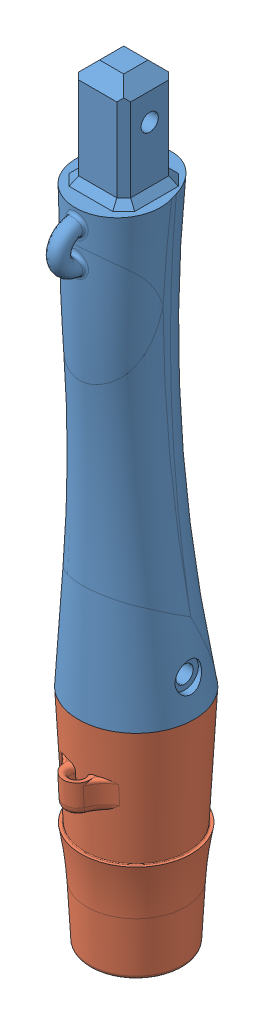
SolidWorks assembly Tibial assemb, configuration Default. Lengths in mm.
Overall size (64.82 366.35 55.64).
2 component instances, 2 part files, 3 mates.
Components (placement in the parent):
- Tibial head with hardware - bone connection - test-1: Tibial head with hardware - bone connection - test [Default] at (117.357 378.302 160.595) size (75.42 296.73 77.35)
- Tibial End - New air plug-1: Tibial End - New air plug [Default] at (73.3348 -40.3659 212.5692) size (42.45 113.08 48.21)
Mates (geometry in assembly coordinates):
- Coincident1: coincident: plane of Tibial head with hardware - bone connection - test-1 through (73.3348 61.2341 212.5692) normal (0 -1 0); plane of Tibial End - New air plug-1 through (73.3348 61.2341 212.5692) normal (0 1 0)
- Coincident2: coincident: plane of Tibial head with hardware - bone connection - test-1 through (82.8598 99.3341 222.0942) normal (0 0 -1); plane of Tibial End - New air plug-1 through (82.8598 92.9841 222.0942) normal (0 0 1)
- Coincident3: coincident: plane of Tibial head with hardware - bone connection - test-1 through (63.8098 99.3341 222.0942) normal (1 0 0); plane of Tibial End - New air plug-1 through (63.8098 92.9841 222.0942) normal (-1 0 0)
